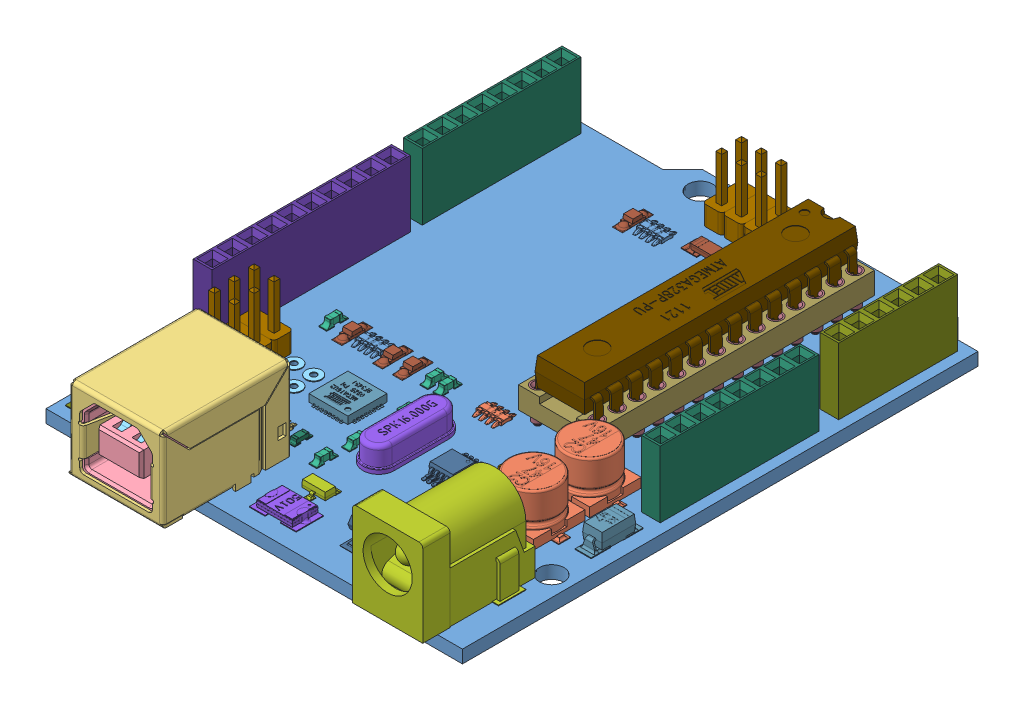
SolidWorks assembly arduino uno, configuration Default. Lengths in mm.
Overall size (53.34 15.25 74.97).
87 component instances, 35 part files, 133 mates.
Components (placement in the parent):
- unoboard blue-1: unoboard blue [Default] at origin size (53.34 1.65 68.58)
- 47uf CAP Dcase-1: 47uf CAP Dcase [Default] at (-9.4141 0 -18.4991) x (0 0 -1) z (1 0 0) size (6.6 5.81 8)
- USB type b-1: USB type b [Default] at (-38.02 0.43 6.35) size (14.34 15.2 16.54)
  - USB SHELL-1: USB SHELL [Default] at origin size (14.34 15.2 16.54)
  - USB core-1: USB core [Default] at origin size (11.3 10.68 15.75)
  - usb top contact-1: usb top contact [Default] at (1.25 6.09 -0.38) size (1 9.67 13.76)
  - usb btm contact-1: usb btm contact [Default] at (1.25 4.41 -0.38) size (1 6.84 11.76)
  - usb btm contact-2: usb btm contact [Default] at (-1.25 4.41 -0.38) size (1 6.84 11.76)
  - usb top contact-2: usb top contact [Default] at (-1.25 6.09 -0.38) size (1 9.67 13.76)
- power jack-1: power jack [Default] at (-7.675 0 1.905) size (11.2 15.2 15.9)
- 47uf CAP Dcase-2: 47uf CAP Dcase [Default] at (-9.4141 0 -25.7132) x (0 0 -1) z (1 0 0) size (6.6 5.81 8)
- crystal-1: crystal [Default] at (-26.162 0 -18.923) x (1 0 0) z (0 0 -1) size (4 5 11)
- 2pin_header__02-1: 2pin_header__02 [Default] at (-46.23 0 -15.75) size (5 11.75 2.54)
- nano - reg-1: nano - reg [Default] at (-17.399 0 -7.747) size (6.5 1.69 8.3)
- led-1: led [Default] at (-34.29 0 -27.94) x (0 0 1) z (-1 0 0) size (4 0.86 1.35)
- 2pin_header__02-2: 2pin_header__02 [Default] at (-30.43 0 -64.91) x (0 0 1) z (-1 0 0) size (5 11.75 2.54)
- dip28-1: dip28 [Default] at (-16.383 1.5 -46.355) x (0 0 -1) z (1 0 0) size (35.48 7.37 10.1)
  - dip28-1: dip28 [Default] at origin size (35.48 2.8 10.1)
  - dip socket pin-1: dip socket pin [Default] at (16.51 2.8 -3.81) size (1.7 7.37 1.7)
  - dip socket pin-2: dip socket pin [Default] at (16.51 2.8 3.81) size (1.7 7.37 1.7)
  - dip socket pin-3: dip socket pin [Default] at (13.97 2.8 -3.81) size (1.7 7.37 1.7)
  - dip socket pin-4: dip socket pin [Default] at (13.97 2.8 3.81) size (1.7 7.37 1.7)
  - dip socket pin-5: dip socket pin [Default] at (11.43 2.8 -3.81) size (1.7 7.37 1.7)
  - dip socket pin-6: dip socket pin [Default] at (11.43 2.8 3.81) size (1.7 7.37 1.7)
  - dip socket pin-7: dip socket pin [Default] at (8.89 2.8 -3.81) size (1.7 7.37 1.7)
  - dip socket pin-8: dip socket pin [Default] at (8.89 2.8 3.81) size (1.7 7.37 1.7)
  - dip socket pin-9: dip socket pin [Default] at (6.35 2.8 -3.81) size (1.7 7.37 1.7)
  - dip socket pin-10: dip socket pin [Default] at (6.35 2.8 3.81) size (1.7 7.37 1.7)
  - dip socket pin-11: dip socket pin [Default] at (3.81 2.8 -3.81) size (1.7 7.37 1.7)
  - dip socket pin-12: dip socket pin [Default] at (3.81 2.8 3.81) size (1.7 7.37 1.7)
  - dip socket pin-13: dip socket pin [Default] at (1.27 2.8 -3.81) size (1.7 7.37 1.7)
  - dip socket pin-14: dip socket pin [Default] at (1.27 2.8 3.81) size (1.7 7.37 1.7)
  - dip socket pin-15: dip socket pin [Default] at (-1.27 2.8 -3.81) size (1.7 7.37 1.7)
  - dip socket pin-16: dip socket pin [Default] at (-1.27 2.8 3.81) size (1.7 7.37 1.7)
  - dip socket pin-17: dip socket pin [Default] at (-3.81 2.8 -3.81) size (1.7 7.37 1.7)
  - dip socket pin-18: dip socket pin [Default] at (-3.81 2.8 3.81) size (1.7 7.37 1.7)
  - dip socket pin-19: dip socket pin [Default] at (-6.35 2.8 -3.81) size (1.7 7.37 1.7)
  - dip socket pin-20: dip socket pin [Default] at (-6.35 2.8 3.81) size (1.7 7.37 1.7)
  - dip socket pin-21: dip socket pin [Default] at (-8.89 2.8 -3.81) size (1.7 7.37 1.7)
  - dip socket pin-22: dip socket pin [Default] at (-8.89 2.8 3.81) size (1.7 7.37 1.7)
  - dip socket pin-23: dip socket pin [Default] at (-11.43 2.8 -3.81) size (1.7 7.37 1.7)
  - dip socket pin-24: dip socket pin [Default] at (-11.43 2.8 3.81) size (1.7 7.37 1.7)
  - dip socket pin-25: dip socket pin [Default] at (-13.97 2.8 -3.81) size (1.7 7.37 1.7)
  - dip socket pin-26: dip socket pin [Default] at (-13.97 2.8 3.81) size (1.7 7.37 1.7)
  - dip socket pin-27: dip socket pin [Default] at (-16.51 2.8 -3.81) size (1.7 7.37 1.7)
  - dip socket pin-28: dip socket pin [Default] at (-16.51 2.8 3.81) size (1.7 7.37 1.7)
- 2pin_header__02-3: 2pin_header__02 [Default] at (-27.89 0 -64.91) x (0 0 1) z (-1 0 0) size (5 11.75 2.54)
- 2pin_header__02-4: 2pin_header__02 [Default] at (-25.35 0 -64.91) x (0 0 1) z (-1 0 0) size (5 11.75 2.54)
- 2pin_header__02-5: 2pin_header__02 [Default] at (-46.23 0 -18.29) size (5 11.75 2.54)
- 2pin_header__02-6: 2pin_header__02 [Default] at (-46.23 0 -20.83) size (5 11.75 2.54)
- atmega16u2-1: atmega16u2 [Default] at (-34.671 0.06 -20) x (1 0 0) z (0 0 -1) size (5.5 1.01 5.5)
- led-2: led [Default] at (-36.83 0 -27.94) x (0 0 1) z (-1 0 0) size (4 0.86 1.35)
- led-3: led [Default] at (-42.037 0 -27.94) x (0 0 1) z (-1 0 0) size (4 0.86 1.35)
- led-4: led [Default] at (-36.576 0 -58.42) x (0 0 1) z (-1 0 0) size (4 0.86 1.35)
- 8 PORT HEADER-3: 8 PORT HEADER [Default] at (-50.8 0 -45.72) x (0 0 -1) z (1 0 0) size (20.32 10.51 2.41)
- 8 PORT HEADER-4: 8 PORT HEADER [Default] at (-2.54 0 -27.94) x (0 0 -1) z (1 0 0) size (20.32 10.51 2.41)
- 6 PORT HEADER-3: 6 PORT HEADER [Default] at (-2.54 0 -50.8) x (0 0 -1) z (1 0 0) size (15.24 10.51 2.41)
- 10 PORT HEADER-1: 10 PORT HEADER [Default] at (-50.8 0 -18.796) x (0 0 -1) z (1 0 0) size (25.4 10.51 2.41)
- ATMEL328P-1: ATMEL328P [Default] at (-16.383 4.3 -46.355) x (0 0 -1) z (1 0 0) size (35 7.27 7.87)
- 102 RESISTOR PACK-1: 102 RESISTOR PACK [Default] at (-33.782 0 -58.42) size (3.2 0.46 3)
- 102 RESISTOR PACK-2: 102 RESISTOR PACK [Default] at (-39.37 0 -27.94) size (3.2 0.46 3)
- 103 RESISTOR PACK-3: 103 RESISTOR PACK [Default] at (-23.876 0 -27.94) size (3.2 0.46 3)
- 220 RESISTOR PACK-1: 220 RESISTOR PACK [Default] at (-36.83 0 -12.827) size (3.2 0.46 3)
- 16mhz crystal - measured-1: 16mhz crystal - measured [Default] at (-24.892 0 -41.275) x (0 0 -1) z (1 0 0) size (3.4 0.8 2)
- PADS001-1: PADS001 [Default] at (-39.878 0.1 -18.288) x (-1 0 0) z (0 0 1) size (4.54 0.1 4.54)
- 603 cap on pad-1: 603 cap on pad [Default] at (-44.45 0 -27.94) x (0 0 -1) z (1 0 0) size (2.76 0.9 1.12)
- ssot3-1: ssot3 [Default] at (-26.5 0 -8.128) x (-1 0 0) z (0 0 -1) size (3 1.13 3.09)
- mf-msmf050-2-1: mf-msmf050-2 [Default] at (-26.5 0 -4.064) size (5.77 1.02 3.72)
- 603 cap on pad-2: 603 cap on pad [Default] at (-29.845 0 -27.94) x (0 0 -1) z (1 0 0) size (2.76 0.9 1.12)
- 603 cap on pad-3: 603 cap on pad [Default] at (-31.496 0 -27.94) x (0 0 -1) z (1 0 0) size (2.76 0.9 1.12)
- lmv358-1: lmv358 [Default] at (-15.24 0 -21.971) x (0 0 -1) z (1 0 0) size (3.7 1.4 2.9)
- 603 cap on pad-4: 603 cap on pad [Default] at (-15.24 0 -18.415) size (2.76 0.9 1.12)
- 603 cap on pad-5: 603 cap on pad [Default] at (-29.845 0 -12.065) x (0 0 1) z (-1 0 0) size (2.76 0.9 1.12)
- 603 cap on pad-6: 603 cap on pad [Default] at (-29.591 0 -22.352) x (0 0 1) z (-1 0 0) size (2.76 0.9 1.12)
- 603 cap on pad-7: 603 cap on pad [Default] at (-29.591 0 -16.002) x (0 0 1) z (-1 0 0) size (2.76 0.9 1.12)
- 603 cap on pad-8: 603 cap on pad [Default] at (-41.91 0 -12.7) x (0 0 1) z (-1 0 0) size (2.76 0.9 1.12)
- lp2985dgkr-1: lp2985dgkr [Default] at (-20.32 0 -19.05) x (0 0 -1) z (1 0 0) size (5.85 1.1 3)
- cd1206 diode-1: cd1206 diode [Default] at (-27.94 0 -59.436) x (0 0 -1) z (1 0 0) size (2.07 0.96 5)
- cd1206 diode-2: cd1206 diode [Default] at (-46.228 0 -13.081) x (0 0 1) z (-1 0 0) size (2.07 0.96 5)
- 603 resistor-1: 603 resistor [Default] at (-29.591 0 -19.05) x (0 0 1) z (-1 0 0) size (2.36 0.61 1.03)
- blm21-1: blm21 [Default] at (-45.085 0 -7.62) x (0 0 -1) z (1 0 0) size (2.76 0.95 1.32)
- m7 diode-1: m7 diode [Default] at (-2.794 0 -21.59) x (0 0 -1) z (1 0 0) size (6.66 2.35 2.5)
- MLC0603-1: MLC0603 [Default] at (-33.655 0 -12.827) x (0 0 -1) z (1 0 0) size (2.36 0.6 1.03)
- MLC0603-2: MLC0603 [Default] at (-39.37 0 -12.827) x (0 0 -1) z (1 0 0) size (2.36 0.6 1.03)
- RESET BUTTON-1: RESET BUTTON [Default] at (-49.403 0 -6.35) size (6.2 3.1 9.6)
  - RESET CORE-1: RESET CORE [Default] at (0 0.1 0) x (-1 0 0) z (0 0 -1) size (6.2 3.1 9.6)
  - RESET-1: RESET [Default] at (0 0.1 0) x (0 0 1) z (-1 0 0) size (7.3 2 6.2)
Mates (geometry in assembly coordinates):
- Distance1: distance = 1.905 mm aligned: plane of power jack-1 through (-7.675 0 1.905) normal (0 0 1); plane of unoboard blue-1 through (0 0 0) normal (0 0 1)
- Coincident2: coincident aligned: plane of unoboard blue-1 through (0 0 0) normal (0 1 0); plane of power jack-1 through (-7.675 0 1.905) normal (0 1 0)
- Coincident3: coincident anti-aligned: plane of unoboard blue-1 through (0 0 0) normal (0 1 0); plane of USB type b-1/USB core-1 through (-38.02 0 6.35) normal (0 -1 0)
- Distance2: distance = 6.35 mm aligned: plane of USB type b-1/USB SHELL-1 through (-38.02 0.43 6.35) normal (0 0 1); plane of unoboard blue-1 through (0 0 0) normal (0 0 1)
- Coincident5: coincident aligned: plane of unoboard blue-1 through (0 0 0) normal (0 1 0); plane of 47uf CAP Dcase-1
- Parallel1: parallel anti-aligned: plane of unoboard blue-1 through (0 0 0) normal (0 0 1); plane of 47uf CAP Dcase-1 through (-9.4141 0 -18.4991) normal (0 0 -1)
- Coincident7: coincident aligned: plane of 47uf CAP Dcase-1 through (-6.1141 1.5 -15.1991) normal (1 0 0); plane of 47uf CAP Dcase-2 through (-6.1141 1.5 -22.4132) normal (1 0 0)
- Coincident8: coincident anti-aligned: plane of unoboard blue-1 through (0 0 0) normal (0 1 0); plane of 47uf CAP Dcase-2 through (-8.1891 0 -25.7132) normal (0 -1 0)
- Distance3: distance = 3.175 mm aligned: plane of power jack-1 through (-3.175 10.5 -1.595) normal (1 0 0); plane of unoboard blue-1 through (0 -1.65 0) normal (1 0 0)
- Distance4: distance = 32 mm aligned: plane of USB type b-1/USB SHELL-1 through (-32 0.43 6.35) normal (1 0 0); plane of unoboard blue-1 through (0 -1.65 0) normal (1 0 0)
- Coincident11: coincident anti-aligned: plane of unoboard blue-1 through (0 0 0) normal (0 1 0); plane of crystal-1 through (-26.162 0 -22.423) normal (0 -1 0)
- Concentric1: concentric aligned: cylinder of unoboard blue-1 through (-26.162 -10 -16.383) axis (0 1 0) radius 0.5; cylinder of crystal-1 through (-26.162 -2 -16.383) axis (0 1 0) radius 0.4
- Concentric2: concentric aligned: cylinder of unoboard blue-1 through (-26.162 -10 -21.463) axis (0 1 0) radius 0.5; cylinder of crystal-1 through (-26.162 -2 -21.463) axis (0 1 0) radius 0.4
- Coincident12: coincident anti-aligned: plane of unoboard blue-1 through (0 0 0) normal (0 1 0); plane of 2pin_header__02-1 through (-44.23 0 -14.98) normal (0 -1 0)
- Distance5: distance = 15.75 mm aligned: plane of 2pin_header__02-1 through (-46.23 0 -15.75) normal (0 0 1); plane of assembly through (0 0 0) normal (0 0 1)
- Distance6: distance = 46.23 mm aligned: plane of 2pin_header__02-1 through (-46.23 0 -15.75) normal (1 0 0); plane of assembly through (0 0 0) normal (1 0 0)
- Coincident15: coincident anti-aligned: plane of unoboard blue-1 through (0 0 0) normal (0 1 0); plane of 2pin_header__02-2 through (-31.2 0 -62.91) normal (0 -1 0)
- Distance7: distance = 64.91 mm aligned: plane of 2pin_header__02-2 through (-30.43 0 -64.91) normal (0 0 1); plane of assembly through (0 0 0) normal (0 0 1)
- Distance8: distance = 30.43 mm anti-aligned: plane of 2pin_header__02-2 through (-30.43 0 -64.91) normal (-1 0 0); plane of assembly through (0 0 0) normal (1 0 0)
- Coincident19: coincident anti-aligned: plane of unoboard blue-1 through (0 0 0) normal (0 1 0); plane of nano - reg-1 through (-17.399 0 -7.747) normal (0 -1 0)
- Concentric3: concentric aligned: cylinder of unoboard blue-1 through (-20.193 -10 -62.865) axis (0 1 0) radius 0.4; cylinder of dip28-1/dip socket pin-1 through (-20.193 33.2926 -62.865) axis (0 1 0) radius 0.25
- Concentric4: concentric aligned: cylinder of unoboard blue-1 through (-12.573 -10 -29.845) axis (0 1 0) radius 0.4; cylinder of dip28-1/dip socket pin-28 through (-12.573 33.2926 -29.845) axis (0 1 0) radius 0.25
- Distance9: distance = 1.5 mm anti-aligned: plane of dip28-1/dip28-1 through (-11.333 1.5 -64.095) normal (0 -1 0); plane of unoboard blue-1 through (0 0 0) normal (0 1 0)
- Coincident21: coincident anti-aligned: plane of unoboard blue-1 through (0 0 0) normal (0 1 0); plane of atmega16u2-1 through (-34.671 0 -20) normal (0 -1 0)
- Distance10: distance = 20 mm anti-aligned: plane of atmega16u2-1 through (-34.671 0.06 -20) normal (0 0 -1); plane of unoboard blue-1 through (0 0 0) normal (0 0 1)
- Distance11: distance = 34.671 mm aligned: plane of atmega16u2-1; plane of unoboard blue-1 through (0 0 0) normal (1 0 0)
- Coincident25: coincident anti-aligned: plane of unoboard blue-1 through (0 0 0) normal (0 1 0); plane of led-1 through (-34.29 0 -28.94) normal (0 -1 0)
- Distance12: distance = 34.29 mm anti-aligned: plane of led-1 through (-34.29 0 -27.94) normal (-1 0 0); plane of unoboard blue-1 through (0 0 0) normal (1 0 0)
- Distance13: distance = 27.94 mm aligned: plane of led-1 through (-34.29 0 -27.94) normal (0 0 1); plane of unoboard blue-1 through (0 0 0) normal (0 0 1)
- Coincident28: coincident aligned: plane of led-2 through (-36.83 0 -28.94) normal (0 -1 0); plane of led-3 through (-42.037 0 -28.94) normal (0 -1 0)
- Coincident29: coincident aligned: plane of led-1 through (-34.29 0 -27.94) normal (0 0 1); plane of led-2 through (-36.83 0 -27.94) normal (0 0 1)
- Coincident30: coincident aligned: plane of led-1 through (-34.29 0 -27.94) normal (0 0 1); plane of led-3 through (-42.037 0 -27.94) normal (0 0 1)
- Distance14: distance = 2.54 mm aligned: plane of led-2 through (-36.83 0 -27.94) normal (-1 0 0); plane of led-1 through (-34.29 0 -27.94) normal (-1 0 0)
- Coincident32: coincident anti-aligned: plane of unoboard blue-1 through (0 0 0) normal (0 1 0); plane of led-2 through (-36.83 0 -28.94) normal (0 -1 0)
- Distance15: distance = 42.037 mm anti-aligned: plane of led-3 through (-42.037 0 -27.94) normal (-1 0 0); plane of unoboard blue-1 through (0 0 0) normal (1 0 0)
- Coincident34: coincident anti-aligned: plane of unoboard blue-1 through (0 0 0) normal (0 1 0); plane of led-4 through (-36.576 0 -59.42) normal (0 -1 0)
- Distance16: distance = 36.576 mm anti-aligned: plane of led-4 through (-36.576 0 -58.42) normal (-1 0 0); plane of unoboard blue-1 through (0 0 0) normal (1 0 0)
- Distance17: distance = 58.42 mm aligned: plane of led-4 through (-36.576 0 -58.42) normal (0 0 1); plane of unoboard blue-1 through (0 0 0) normal (0 0 1)
- Coincident37: coincident aligned: plane of unoboard blue-1 through (0 0 0) normal (0 1 0); plane of 8 PORT HEADER-4
- Coincident38: coincident aligned: plane of unoboard blue-1 through (0 0 0) normal (0 1 0); plane of 8 PORT HEADER-3
- Parallel2: parallel aligned: plane of unoboard blue-1 through (0 0 0) normal (1 0 0); plane of 8 PORT HEADER-4 through (-2.54 0 -27.94) normal (1 0 0)
- Parallel3: parallel aligned: plane of unoboard blue-1 through (0 0 0) normal (1 0 0); plane of 8 PORT HEADER-3 through (-50.8 0 -45.72) normal (1 0 0)
- Concentric5: concentric aligned: cylinder of unoboard blue-1 through (-2.54 -1.65 -27.94) axis (0 1 0) radius 0.4; line of 8 PORT HEADER-4 through (-2.54 -2.5255 -27.94) axis (0 1 0)
- Concentric6: concentric aligned: cylinder of unoboard blue-1 through (-50.8 -1.65 -45.72) axis (0 1 0) radius 0.4; line of 8 PORT HEADER-3 through (-50.8 -2.5255 -45.72) axis (0 1 0)
- Coincident43: coincident aligned: plane of unoboard blue-1 through (0 0 0) normal (0 1 0); plane of 10 PORT HEADER-1
- Coincident44: coincident aligned: plane of unoboard blue-1 through (0 0 0) normal (0 1 0); plane of 6 PORT HEADER-3
- Parallel4: parallel aligned: plane of unoboard blue-1 through (0 0 0) normal (1 0 0); plane of 6 PORT HEADER-3 through (-2.54 0 -50.8) normal (1 0 0)
- Parallel5: parallel aligned: plane of unoboard blue-1 through (0 0 0) normal (1 0 0); plane of 10 PORT HEADER-1 through (-50.8 0 -18.796) normal (1 0 0)
- Concentric7: concentric aligned: cylinder of unoboard blue-1 through (-50.8 -1.65 -18.796) axis (0 1 0) radius 0.4; line of 10 PORT HEADER-1 through (-50.8 -2.5255 -18.796) axis (0 1 0)
- Concentric9: concentric aligned: cylinder of unoboard blue-1 through (-2.54 -1.65 -50.8) axis (0 1 0) radius 0.4; line of 6 PORT HEADER-3 through (-2.54 -2.5255 -50.8) axis (0 1 0)
- Coincident50: coincident aligned: plane of dip28-1/dip28-1 through (-16.383 1.5 -46.355) normal (0 0 -1); plane of ATMEL328P-1 through (-16.383 4.3 -46.355) normal (0 0 -1)
- Coincident51: coincident aligned: plane of dip28-1/dip28-1 through (-16.383 1.5 -46.355) normal (1 0 0); plane of ATMEL328P-1 through (-16.383 4.3 -46.355) normal (1 0 0)
- Coincident52: coincident aligned: plane of dip28-1/dip28-1 through (-11.333 4.3 -64.095) normal (0 1 0); plane of ATMEL328P-1
- Distance18: distance = 7.747 mm: plane of nano - reg-1 through (-17.399 0 -7.747) normal (0 0 1); line of unoboard blue-1 through (-53.34 0 0) axis (1 0 0)
- Distance19: distance = 17.399 mm aligned: plane of nano - reg-1 through (-17.399 0 -7.747) normal (1 0 0); plane of unoboard blue-1 through (0 0 0) normal (1 0 0)
- Coincident55: coincident anti-aligned: plane of unoboard blue-1 through (0 0 0) normal (0 1 0); plane of 102 RESISTOR PACK-1 through (-33.982 0 -59.12) normal (0 -1 0)
- Distance20: distance = 33.782 mm aligned: plane of 102 RESISTOR PACK-1 through (-33.782 0 -58.42) normal (1 0 0); plane of unoboard blue-1 through (0 0 0) normal (1 0 0)
- Distance21: distance = 58.42 mm aligned: plane of 102 RESISTOR PACK-1 through (-33.782 0 -58.42) normal (0 0 1); plane of unoboard blue-1 through (0 0 0) normal (0 0 1)
- Coincident58: coincident aligned: plane of 102 RESISTOR PACK-2 through (-39.37 0 -27.94) normal (0 1 0); plane of 103 RESISTOR PACK-3 through (-23.876 0 -27.94) normal (0 1 0)
- Coincident59: coincident aligned: plane of unoboard blue-1 through (0 0 0) normal (0 1 0); plane of 103 RESISTOR PACK-3 through (-23.876 0 -27.94) normal (0 1 0)
- Coincident60: coincident aligned: plane of 102 RESISTOR PACK-2 through (-39.37 0 -27.94) normal (0 0 1); plane of 103 RESISTOR PACK-3 through (-23.876 0 -27.94) normal (0 0 1)
- Distance22: distance = 23.876 mm aligned: plane of 103 RESISTOR PACK-3 through (-23.876 0 -27.94) normal (1 0 0); plane of unoboard blue-1 through (0 0 0) normal (1 0 0)
- Distance23: distance = 39.37 mm aligned: plane of 102 RESISTOR PACK-2 through (-39.37 0 -27.94) normal (1 0 0); plane of unoboard blue-1 through (0 0 0) normal (1 0 0)
- Distance24: distance = 27.94 mm aligned: plane of 102 RESISTOR PACK-2 through (-39.37 0 -27.94) normal (0 0 1); plane of unoboard blue-1 through (0 0 0) normal (0 0 1)
- Distance25: distance = 12.827 mm aligned: plane of 220 RESISTOR PACK-1 through (-36.83 0 -12.827) normal (0 0 1); plane of unoboard blue-1 through (0 0 0) normal (0 0 1)
- Distance26: distance = 36.83 mm aligned: plane of 220 RESISTOR PACK-1 through (-36.83 0 -12.827) normal (1 0 0); plane of unoboard blue-1 through (0 0 0) normal (1 0 0)
- Coincident66: coincident aligned: plane of unoboard blue-1 through (0 0 0) normal (0 1 0); plane of 220 RESISTOR PACK-1 through (-36.83 0 -12.827) normal (0 1 0)
- Coincident67: coincident anti-aligned: plane of unoboard blue-1 through (0 0 0) normal (0 1 0); plane of 16mhz crystal - measured-1 through (-24.892 0 -41.275) normal (0 -1 0)
- Distance27: distance = 41.275 mm anti-aligned: plane of 16mhz crystal - measured-1 through (-24.892 0 -41.275) normal (0 0 -1); plane of unoboard blue-1 through (0 0 0) normal (0 0 1)
- Distance28: distance = 24.892 mm aligned: plane of 16mhz crystal - measured-1 through (-24.892 0 -41.275) normal (1 0 0); plane of unoboard blue-1 through (0 0 0) normal (1 0 0)
- Coincident70: coincident anti-aligned: plane of unoboard blue-1 through (0 0 0) normal (0 1 0); plane of PADS001-1 through (-42.418 0 -18.288) normal (0 -1 0)
- Distance29: distance = 18.288 mm aligned: plane of PADS001-1 through (-39.878 0.1 -18.288) normal (0 0 1); plane of unoboard blue-1 through (0 0 0) normal (0 0 1)
- Distance30: distance = 39.878 mm anti-aligned: plane of PADS001-1; plane of unoboard blue-1 through (0 0 0) normal (1 0 0)
- Distance31: distance = 4.064 mm aligned: plane of mf-msmf050-2-1 through (-26.5 0 -4.064) normal (0 0 1); plane of unoboard blue-1 through (0 0 0) normal (0 0 1)
- Distance32: distance = 26.5 mm aligned: plane of mf-msmf050-2-1 through (-26.5 0 -4.064) normal (1 0 0); plane of unoboard blue-1 through (0 0 0) normal (1 0 0)
- Coincident72: coincident aligned: plane of unoboard blue-1 through (0 0 0) normal (0 1 0); plane of mf-msmf050-2-1 through (-26.5 0 -4.064) normal (0 1 0)
- Distance33: distance = 8.128 mm anti-aligned: plane of unoboard blue-1 through (0 0 0) normal (0 0 1); plane of ssot3-1 through (-26.5 0 -8.128) normal (0 0 -1)
- Coincident74: coincident anti-aligned: plane of ssot3-1 through (-26.5 0 -8.128) normal (-1 0 0); plane of mf-msmf050-2-1 through (-26.5 0 -4.064) normal (1 0 0)
- Coincident75: coincident aligned: plane of unoboard blue-1 through (0 0 0) normal (0 1 0); plane of ssot3-1
- Coincident76: coincident anti-aligned: plane of led-1 through (-34.29 0 -27.94) normal (0 0 1); plane of 603 cap on pad-1 through (-44.45 0 -27.94) normal (0 0 -1)
- Coincident77: coincident aligned: plane of unoboard blue-1 through (0 0 0) normal (0 1 0); plane of 603 cap on pad-1
- Distance34: distance = 44.45 mm aligned: plane of 603 cap on pad-1 through (-44.45 0 -27.94) normal (1 0 0); plane of unoboard blue-1 through (0 0 0) normal (1 0 0)
- Coincident79: coincident aligned: plane of 603 cap on pad-2; plane of 603 cap on pad-3
- Coincident80: coincident aligned: plane of 603 cap on pad-2 through (-29.845 0 -27.94) normal (0 0 -1); plane of 603 cap on pad-3 through (-31.496 0 -27.94) normal (0 0 -1)
- Coincident81: coincident aligned: plane of unoboard blue-1 through (0 0 0) normal (0 1 0); plane of 603 cap on pad-2
- Coincident82: coincident aligned: plane of 603 cap on pad-1 through (-44.45 0 -27.94) normal (0 0 -1); plane of 603 cap on pad-2 through (-29.845 0 -27.94) normal (0 0 -1)
- Distance36: distance = 29.845 mm aligned: plane of 603 cap on pad-2 through (-29.845 0 -27.94) normal (1 0 0); plane of unoboard blue-1 through (0 0 0) normal (1 0 0)
- Distance37: distance = 31.496 mm aligned: plane of 603 cap on pad-3 through (-31.496 0 -27.94) normal (1 0 0); plane of unoboard blue-1 through (0 0 0) normal (1 0 0)
- Distance38: distance = 15.24 mm aligned: plane of unoboard blue-1 through (0 0 0) normal (1 0 0); plane of lmv358-1 through (-15.24 0 -21.971) normal (1 0 0)
- Distance39: distance = 21.971 mm anti-aligned: plane of lmv358-1 through (-15.24 0 -21.971) normal (0 0 -1); plane of unoboard blue-1 through (0 0 0) normal (0 0 1)
- Coincident88: coincident aligned: plane of unoboard blue-1 through (0 0 0) normal (0 1 0); plane of lmv358-1
- Distance40: distance = 18.415 mm aligned: plane of 603 cap on pad-4 through (-15.24 0 -18.415) normal (0 0 1); plane of unoboard blue-1 through (0 0 0) normal (0 0 1)
- Distance41: distance = 15.24 mm aligned: plane of 603 cap on pad-4 through (-15.24 0 -18.415) normal (1 0 0); plane of unoboard blue-1 through (0 0 0) normal (1 0 0)
- Coincident91: coincident aligned: plane of unoboard blue-1 through (0 0 0) normal (0 1 0); plane of 603 cap on pad-4 through (-15.24 0 -18.415) normal (0 1 0)
- Coincident92: coincident aligned: plane of unoboard blue-1 through (0 0 0) normal (0 1 0); plane of 603 cap on pad-7
- Coincident93: coincident aligned: plane of unoboard blue-1 through (0 0 0) normal (0 1 0); plane of 603 cap on pad-6
- Coincident94: coincident aligned: plane of 603 cap on pad-5; plane of unoboard blue-1 through (0 0 0) normal (0 1 0)
- Coincident95: coincident aligned: plane of 603 cap on pad-8; plane of unoboard blue-1 through (0 0 0) normal (0 1 0)
- Coincident96: coincident aligned: plane of 603 cap on pad-7 through (-29.591 0 -16.002) normal (-1 0 0); plane of 603 cap on pad-6 through (-29.591 0 -22.352) normal (-1 0 0)
- Distance42: distance = 29.591 mm anti-aligned: plane of 603 cap on pad-7 through (-29.591 0 -16.002) normal (-1 0 0); plane of unoboard blue-1 through (0 0 0) normal (1 0 0)
- Distance43: distance = 22.352 mm: plane of 603 cap on pad-6 through (-29.591 0 -22.352) normal (0 0 1); line of unoboard blue-1 through (-53.34 0 0) axis (1 0 0)
- Distance44: distance = 16.002 mm aligned: plane of 603 cap on pad-7 through (-29.591 0 -16.002) normal (0 0 1); plane of unoboard blue-1 through (0 0 0) normal (0 0 1)
- Distance45: distance = 29.845 mm anti-aligned: plane of 603 cap on pad-5 through (-29.845 0 -12.065) normal (-1 0 0); plane of unoboard blue-1 through (0 0 0) normal (1 0 0)
- Distance46: distance = 12.065 mm aligned: plane of 603 cap on pad-5 through (-29.845 0 -12.065) normal (0 0 1); plane of unoboard blue-1 through (0 0 0) normal (0 0 1)
- Distance47: distance = 41.91 mm anti-aligned: plane of 603 cap on pad-8 through (-41.91 0 -12.7) normal (-1 0 0); plane of unoboard blue-1 through (0 0 0) normal (1 0 0)
- Distance48: distance = 12.7 mm aligned: plane of 603 cap on pad-8 through (-41.91 0 -12.7) normal (0 0 1); plane of unoboard blue-1 through (0 0 0) normal (0 0 1)
- Distance49: distance = 20.32 mm aligned: plane of lp2985dgkr-1 through (-20.32 0 -19.05) normal (1 0 0); plane of unoboard blue-1 through (0 0 0) normal (1 0 0)
- Distance50: distance = 19.05 mm anti-aligned: plane of lp2985dgkr-1 through (-20.32 0 -19.05) normal (0 0 -1); plane of unoboard blue-1 through (0 0 0) normal (0 0 1)
- Coincident99: coincident aligned: plane of unoboard blue-1 through (0 0 0) normal (0 1 0); plane of lp2985dgkr-1
- Distance51: distance = 27.94 mm aligned: plane of cd1206 diode-1 through (-27.94 0 -59.436) normal (1 0 0); plane of unoboard blue-1 through (0 0 0) normal (1 0 0)
- Distance52: distance = 59.436 mm anti-aligned: plane of cd1206 diode-1 through (-27.94 0 -59.436) normal (0 0 -1); plane of unoboard blue-1 through (0 0 0) normal (0 0 1)
- Coincident102: coincident aligned: plane of unoboard blue-1 through (0 0 0) normal (0 1 0); plane of cd1206 diode-1
- Distance53: distance = 46.228 mm anti-aligned: plane of cd1206 diode-2 through (-46.228 0 -13.081) normal (-1 0 0); plane of unoboard blue-1 through (0 0 0) normal (1 0 0)
- Distance54: distance = 13.081 mm aligned: plane of unoboard blue-1 through (0 0 0) normal (0 0 1); plane of cd1206 diode-2 through (-46.228 0 -13.081) normal (0 0 1)
- Coincident105: coincident aligned: plane of unoboard blue-1 through (0 0 0) normal (0 1 0); plane of cd1206 diode-2
- Distance55: distance = 29.591 mm anti-aligned: plane of 603 resistor-1 through (-29.591 0 -19.05) normal (-1 0 0); plane of unoboard blue-1 through (0 0 0) normal (1 0 0)
- Distance56: distance = 19.05 mm aligned: plane of 603 resistor-1 through (-29.591 0 -19.05) normal (0 0 1); plane of unoboard blue-1 through (0 0 0) normal (0 0 1)
- Coincident108: coincident aligned: plane of unoboard blue-1 through (0 0 0) normal (0 1 0); plane of 603 resistor-1
- Distance57: distance = 7.62 mm anti-aligned: plane of blm21-1 through (-45.085 0 -7.62) normal (0 0 -1); plane of unoboard blue-1 through (0 0 0) normal (0 0 1)
- Distance58: distance = 45.085 mm aligned: plane of blm21-1 through (-45.085 0 -7.62) normal (1 0 0); plane of unoboard blue-1 through (0 0 0) normal (1 0 0)
- Distance59: distance = 21.59 mm anti-aligned: plane of m7 diode-1 through (-2.794 0 -21.59) normal (0 0 -1); plane of unoboard blue-1 through (0 0 0) normal (0 0 1)
- Distance60: distance = 2.794 mm aligned: plane of m7 diode-1 through (-2.794 0 -21.59) normal (1 0 0); plane of unoboard blue-1 through (0 0 0) normal (1 0 0)
- Coincident113: coincident aligned: plane of unoboard blue-1 through (0 0 0) normal (0 1 0); plane of m7 diode-1
- Coincident114: coincident anti-aligned: plane of 220 RESISTOR PACK-1 through (-36.83 0 -12.827) normal (0 0 1); plane of MLC0603-1 through (-33.655 0 -12.827) normal (0 0 -1)
- Distance61: distance = 33.655 mm aligned: plane of MLC0603-1 through (-33.655 0 -12.827) normal (1 0 0); plane of unoboard blue-1 through (0 0 0) normal (1 0 0)
- Coincident115: coincident aligned: plane of unoboard blue-1 through (0 0 0) normal (0 1 0); plane of MLC0603-1
- Coincident116: coincident aligned: plane of unoboard blue-1 through (0 0 0) normal (0 1 0); plane of blm21-1
- Coincident117: coincident anti-aligned: plane of 220 RESISTOR PACK-1 through (-36.83 0 -12.827) normal (0 0 1); plane of MLC0603-2 through (-39.37 0 -12.827) normal (0 0 -1)
- Coincident118: coincident aligned: plane of unoboard blue-1 through (0 0 0) normal (0 1 0); plane of MLC0603-2
- Distance62: distance = 39.37 mm aligned: plane of MLC0603-2 through (-39.37 0 -12.827) normal (1 0 0); plane of unoboard blue-1 through (0 0 0) normal (1 0 0)
- Distance63: distance = 49.403 mm aligned: plane of RESET BUTTON-1 through (-49.403 0 -6.35) normal (1 0 0); plane of unoboard blue-1 through (0 0 0) normal (1 0 0)
- Distance64: distance = 6.35 mm aligned: plane of RESET BUTTON-1; plane of unoboard blue-1 through (0 0 0) normal (0 0 1)
- Coincident122: coincident aligned: plane of unoboard blue-1 through (0 0 0) normal (0 1 0); plane of RESET BUTTON-1 through (-49.403 0 -6.35) normal (0 1 0)
